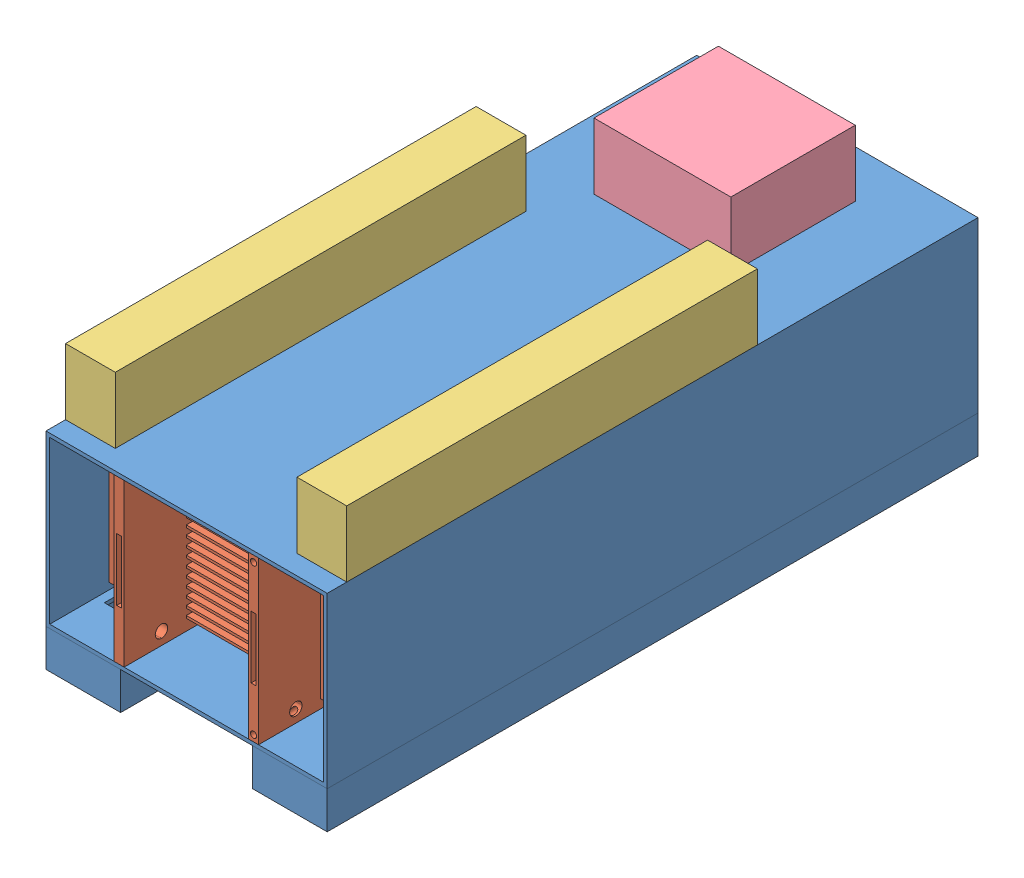
SolidWorks assembly Final_assembly - Copy, configuration Default. Lengths in mm.
Overall size (226 219 523).
7 component instances, 4 part files, 0 mates.
Components (placement in the parent):
- Final_assembly.STEP-1: Final_assembly.STEP [Default] at origin size (226 219 523)
  - Assem1.STEP-1: Assem1.STEP [Default] at (229.3481 314.0398 107.2008) size (226 193 523)
  - Fin Plate.STEP-1: Fin Plate.STEP [Default] at (279.138 249.0398 207.2008) x (0 0 1) z (-1 0 0) size (420 130 108)
  - Fin Plate.STEP-2: Fin Plate.STEP [Default] at (179.138 249.0398 627.2008) x (0 0 -1) z (1 0 0) size (420 130 108)
  - Cleanwater_Container.STEP-1: Cleanwater_Container.STEP [Default] at (134.6646 432.0398 595.4244) x (1 0 0) z (0 0 -1) size (40 53 330)
  - Cleanwater_Container.STEP-2: Cleanwater_Container.STEP [Default] at (324.0316 432.0398 297.6129) x (-1 0 0) z (0 0 1) size (40 53 330)
  - Dirtywater_Container.STEP-1: Dirtywater_Container.STEP [Default] at (238.1156 435.0398 211.5676) x (1 0 0) z (0 0 -1) size (110 53 100)
